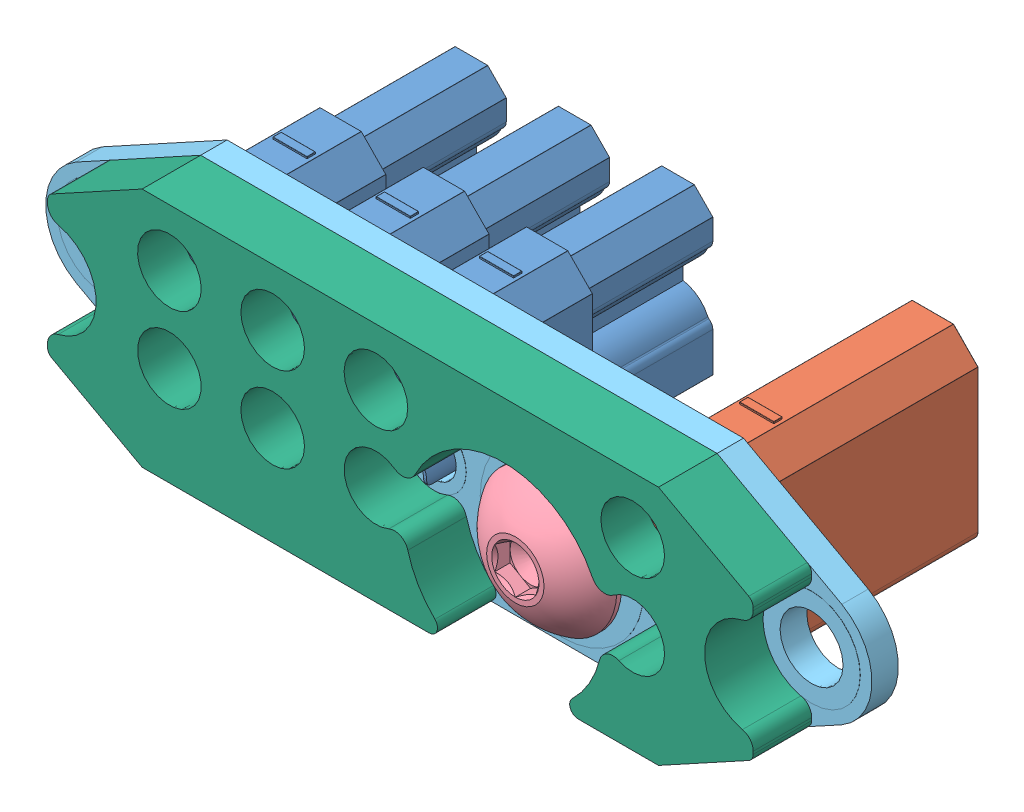
SolidWorks assembly powerswitch_me2__, configuration Default. Lengths in mm.
Overall size (48 14 17.55).
9 component instances, 6 part files, 0 mates.
Components (placement in the parent):
- just cuz_SwitchBoard.stp-1: just cuz_SwitchBoard.stp [Default] at origin size (48 14 17.55)
  - XT30_Female.stp-1: XT30_Female.stp [Default] at (-4.7913 -1.9356 -6.5462) x (-1 0 0) z (0 0 -1) size (5.25 10.45 15.6)
  - XT30_Male.stp-1: XT30_Male.stp [Default] at (4.8749 -1.9112 -14.0462) size (5.25 10.45 15.5)
  - 8-32 PEM Nut Insert.stp-1: 8-32 PEM Nut Insert.stp [Default] at (0 0 -4.0856) x (1 0 0) z (0 -1 0) size (8.64 3.94 8.64)
  - XT30_Female.stp-2: XT30_Female.stp [Default] at (-10.7913 -1.9356 -6.5462) x (-1 0 0) z (0 0 -1) size (5.25 10.45 15.6)
  - XT30_Female.stp-3: XT30_Female.stp [Default] at (-16.7913 -1.9356 -6.5462) x (-1 0 0) z (0 0 -1) size (5.25 10.45 15.6)
  - 8-32 3-16 NO THREADS_ Button Head Hex Drive Screw.stp-1: 8-32 3-16 NO THREADS_ Button Head Hex Drive Screw.stp [Default] at (0 0 -0.7667) x (-1 0 0) z (0 0 1) size (7.92 7.92 6.97)
  - Switch PD Board V1.3 Bottom Connectors.stp-1: Switch PD Board V1.3 Bottom Connectors.stp [Default] at origin size (48 14 1.56)
  - Switch PD Board V1.3 Bottom Connectors-0.stp-1: Switch PD Board V1.3 Bottom Connectors-0.stp [Default] at origin size (41 14 3.4)
